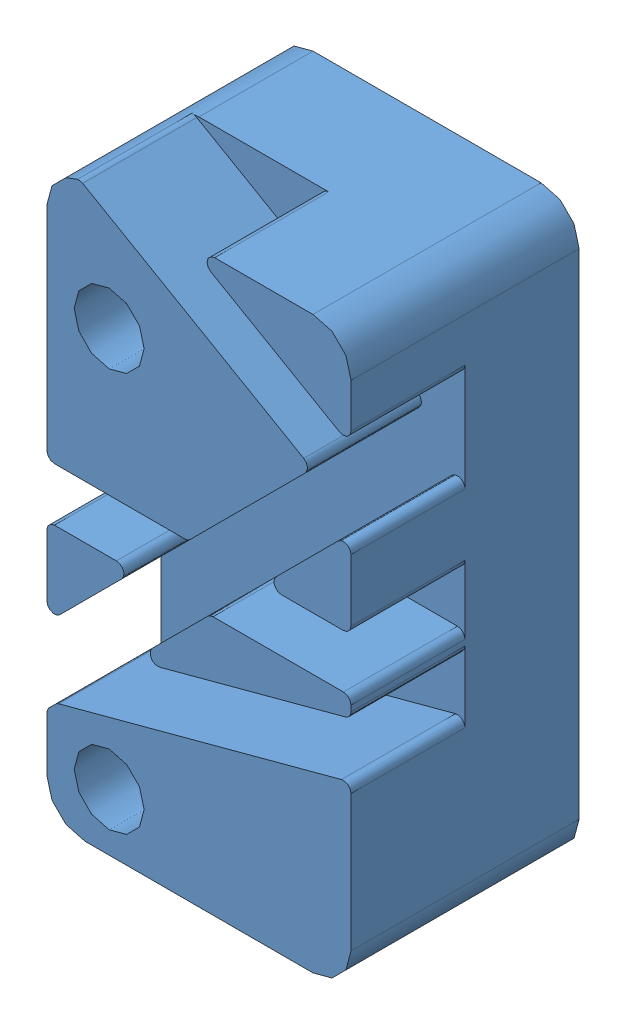
SolidWorks assembly Assem2, configuration Default. Lengths in mm.
Overall size (54.47 100.33 60.64).
5 component instances, 3 part files, 8 mates.
Components (placement in the parent):
- cart block-1: cart block [Default] at origin size (86.84 153.04 77.67)
- cam-1: cam [Default] at (-15 28.575 25.781) x (0.906773 -0.421619 0) z (0 0 -1) size (24.96 14.33 60.64)
- cam-2: cam [Default] at (-15 -38.1 25.781) x (-0.999094 -0.042563 0) z (0 0 -1) size (24.96 14.33 60.64)
- socket button head cap screw_ai-1: socket button head cap screw_ai [SBHCSCREW 0.25-20x0.625-HX-N] at (-15 -38.1 29.1338) x (0 0 -1) z (1 0 0) size (19.23 11.1 11.1)
- socket button head cap screw_ai-2: socket button head cap screw_ai [SBHCSCREW 0.25-20x0.625-HX-N] at (-15 28.575 29.1338) x (0 0 -1) z (0.664585 -0.747213 0) size (19.23 11.1 11.1)
Mates (geometry in assembly coordinates):
- Concentric1: concentric anti-aligned: cylinder of cart block-1 through (-15 28.575 38.1) axis (0 0 -1) radius 4.9022; cylinder of cam-1 through (-15 28.575 0.381) axis (0 0 1) radius 4.7625
- Concentric2: concentric anti-aligned: cylinder of cart block-1 through (-15 -38.1 38.1) axis (0 0 -1) radius 4.9022; cylinder of cam-2 through (-15 -38.1 0.381) axis (0 0 1) radius 4.7625
- Concentric3: concentric aligned: cylinder of cam-1 through (-15 28.575 6.731) axis (0 0 1) radius 2.5527; cylinder of socket button head cap screw_ai-2 through (-15 28.575 29.1338) axis (0 0 1) radius 3.175
- Coincident1: coincident anti-aligned: plane of cam-1 through (-15 28.575 25.781) normal (0 0 1); plane of socket button head cap screw_ai-2 through (-12.6276 30.6851 25.781) normal (0 0 -1)
- Coincident2: coincident anti-aligned: plane of cart block-1 through (0 0 25.781) normal (0 0 1); plane of socket button head cap screw_ai-2 through (-12.6276 30.6851 25.781) normal (0 0 -1)
- Concentric4: concentric aligned: cylinder of cam-2 through (-15 -38.1 6.731) axis (0 0 1) radius 2.5527; cylinder of socket button head cap screw_ai-1 through (-15 -38.1 29.1338) axis (0 0 1) radius 3.175
- Coincident3: coincident anti-aligned: plane of cam-2 through (-15 -38.1 25.781) normal (0 0 1); plane of socket button head cap screw_ai-1 through (-15 -34.925 25.781) normal (0 0 -1)
- Coincident4: coincident anti-aligned: plane of cart block-1 through (0 0 25.781) normal (0 0 1); plane of socket button head cap screw_ai-1 through (-15 -34.925 25.781) normal (0 0 -1)
